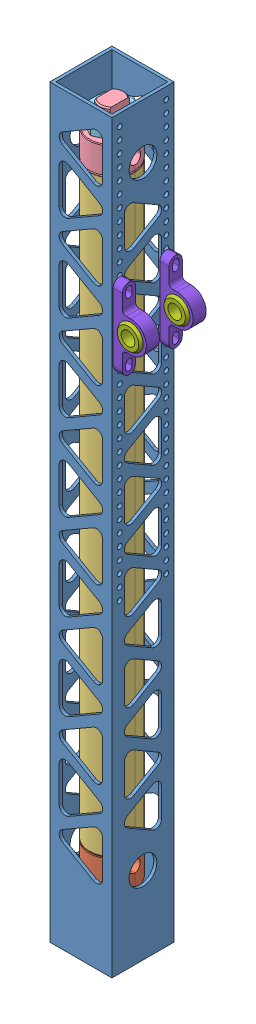
SolidWorks assembly Assem1, configuration Default. Lengths in mm.
Overall size (97.63 762 76.62).
14 component instances, 8 part files, 5 mates.
Components (placement in the parent):
- Post Large-1: Post Large [Default] at (-53.5547 -392.3452 35.9679) size (63.5 762 63.5)
- SR_2422_DP-1: SR_2422_DP [Default] at (-53.5547 -354.2452 35.9679) x (0 1 0) z (1 0 0) size (739.9 46.85 49.1)
  - _24R000_0_rod_guide_4-1: _24R000_0_rod_guide_4 [Default] at origin size (60.33 46.85 46.85)
  - _24R_23_73350SR_6-1: _24R_23_73350SR_6 [Default] at (53.3908 0 0) size (604.74 46.85 46.85)
  - _24P0000_rear_head_8-1: _24P0000_rear_head_8 [Default] at (649.351 0 0) size (60.33 46.85 46.96)
  - _D_1331_10-1: _D_1331_10 [Default] at (686.6382 0 0) x (0 0 -1) z (-1 0 0) size (49.1 44 13.97)
  - _D_1331_10-2: _D_1331_10 [Default] at (16.6624 0 0) x (0 0 -1) z (1 0 0) size (49.1 44 13.97) (hidden)
  - _SR_2422_DP0000_rod_13-1: _SR_2422_DP0000_rod_13 [Default] at origin size (679.58 44.69 44.69)
- KSTM_14_1-1: KSTM_14_1 [Default] at (-3.6772 183.8548 12.1554) x (0 1 0) z (1 0 0) size (82 29 34)
  - 2019_02_09__03-29-56-477-1: 2019_02_09__03-29-56-477 [Default] at origin size (29 19 29)
  - 2019_02_09__03-29-56-477_2-1: 2019_02_09__03-29-56-477_2 [Default] at origin size (82 29 34)
- KSTM_14_1-2: KSTM_14_1 [Default] at (-3.8047 183.8548 59.7804) x (0 1 0) z (1 0 0) size (82 29 34)
  - 2019_02_09__03-29-56-477-1: 2019_02_09__03-29-56-477 [Default] at origin size (29 19 29)
  - 2019_02_09__03-29-56-477_2-1: 2019_02_09__03-29-56-477_2 [Default] at origin size (82 29 34)
Mates (geometry in assembly coordinates):
- Concentric2: concentric aligned: circle of Post Large-1; circle of SR_2422_DP-1/_24R000_0_rod_guide_4-1
- Distance1: distance = 57.15 mm aligned: plane of Post Large-1 through (-53.5547 -392.3452 35.9679) normal (0 -1 0); plane of SR_2422_DP-1/_24R000_0_rod_guide_4-1 through (-53.5547 -335.1952 35.9679) normal (0 -1 0)
- Concentric3: concentric aligned: circle of Post Large-1; circle of KSTM_14_1-1/2019_02_09__03-29-56-477_2-1
- Concentric4: concentric: circle of Post Large-1; circle of KSTM_14_1-2/2019_02_09__03-29-56-477_2-1
- Coincident2: coincident anti-aligned: plane of Post Large-1 through (-21.8047 369.6548 4.2179) normal (1 0 0); plane of KSTM_14_1-2/2019_02_09__03-29-56-477_2-1 through (-21.8047 183.8548 66.5304) normal (-1 0 0)
